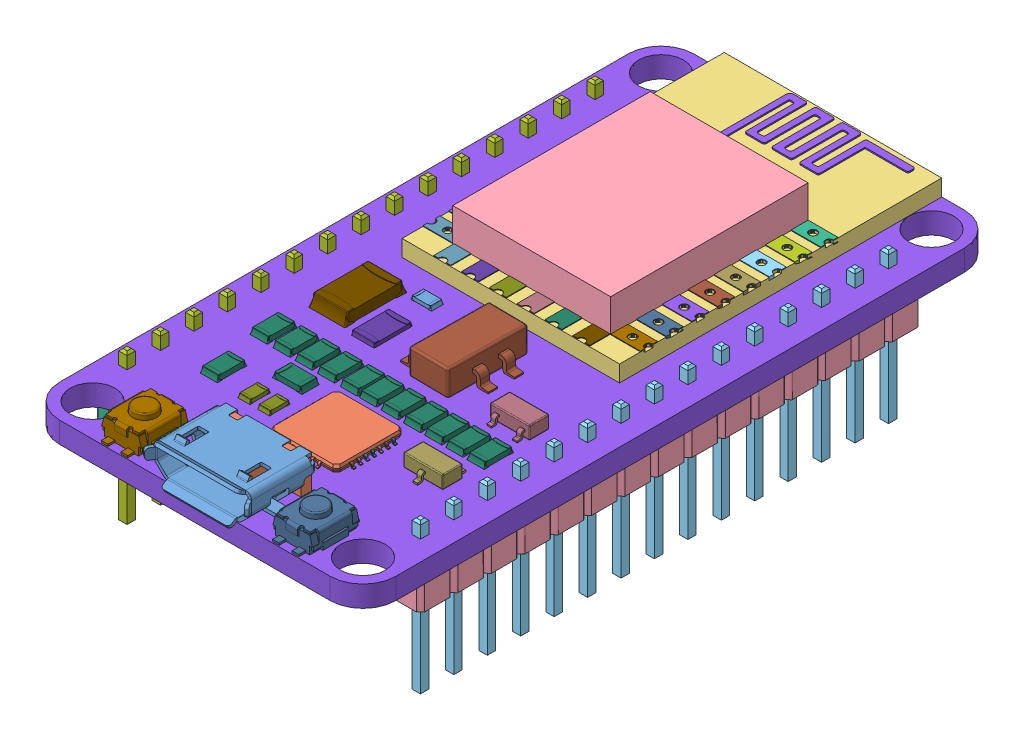
SolidWorks assembly Nodemcu, configuration Default. Lengths in mm.
Overall size (25.55 14.09 48.82).
166 component instances, 58 part files, 0 mates.
Components (placement in the parent):
- ESP8266 v7.stp-1: ESP8266 v7.stp [Default] at origin size (25.55 14.09 48.82)
  - micro usb v1.stp-1: micro usb v1.stp [Default] at (12.6689 12.0548 1.95) x (0 -1 0) z (-1 0 0) size (3.25 6.18 8)
    - micro usb shell.stp-1: micro usb shell.stp [Default] at (10.11 -1.95 -0.7124) x (0 0 -1) z (0 1 0) size (8 2.95 5.63)
    - micro usb internal.stp-1: micro usb internal.stp [Default] at (10.36 -1.95 -0.7124) x (0 0 -1) z (0 1 0) size (6.9 2.9 4)
    - micro usb contact.stp-1: micro usb contact.stp [Default] at (10.36 -2.05 -2.0124) x (0 0 -1) z (0 1 0) size (0.2 1.3 4.65)
    - micro usb contact.stp-2: micro usb contact.stp [Default] at (10.36 -2.05 -1.3624) x (0 0 -1) z (0 1 0) size (0.2 1.3 4.65)
    - micro usb contact.stp-3: micro usb contact.stp [Default] at (10.36 -2.05 -0.7124) x (0 0 -1) z (0 1 0) size (0.2 1.3 4.65)
    - micro usb contact.stp-4: micro usb contact.stp [Default] at (10.36 -2.05 -0.0624) x (0 0 -1) z (0 1 0) size (0.2 1.3 4.65)
    - micro usb contact.stp-5: micro usb contact.stp [Default] at (10.36 -2.05 0.5876) x (0 0 -1) z (0 1 0) size (0.2 1.3 4.65)
  - Placa Base.stp-1: Placa Base.stp [Default] at origin size (25.55 11.43 48.19)
    - Pin Header 1x15 TH Pitch 2.54mm v3 v1.stp-1: Pin Header 1x15 TH Pitch 2.54mm v3 v1.stp [Default] at (24.996 0.1484 -10.5049) x (0 0 -1) z (0 1 0) size (38.1 2.54 11.43)
      - asm_pin.stp-1: asm_pin.stp [Default] at (-4.318 1.27 0.0014) x (1 0 0) z (0 0 -1) size (2.54 2.54 11.43)
        - spacer.stp-1: spacer.stp [Default] at origin size (2.54 2.54 2.54)
        - pin.stp-1: pin.stp [Default] at origin size (0.64 0.64 11.43)
      - asm_pin_1.stp-1: asm_pin_1.stp [Default] at (-1.778 1.27 0.0014) x (1 0 0) z (0 0 -1) size (2.54 2.54 11.43)
        - spacer.stp-1: spacer.stp [Default] at origin size (2.54 2.54 2.54)
        - pin.stp-1: pin.stp [Default] at origin size (0.64 0.64 11.43)
      - asm_pin_2.stp-1: asm_pin_2.stp [Default] at (0.762 1.27 0.0014) x (1 0 0) z (0 0 -1) size (2.54 2.54 11.43)
        - spacer.stp-1: spacer.stp [Default] at origin size (2.54 2.54 2.54)
        - pin.stp-1: pin.stp [Default] at origin size (0.64 0.64 11.43)
      - asm_pin_3.stp-1: asm_pin_3.stp [Default] at (3.302 1.27 0.0014) x (1 0 0) z (0 0 -1) size (2.54 2.54 11.43)
        - spacer.stp-1: spacer.stp [Default] at origin size (2.54 2.54 2.54)
        - pin.stp-1: pin.stp [Default] at origin size (0.64 0.64 11.43)
      - asm_pin_4.stp-1: asm_pin_4.stp [Default] at (5.842 1.27 0.0014) x (1 0 0) z (0 0 -1) size (2.54 2.54 11.43)
        - spacer.stp-1: spacer.stp [Default] at origin size (2.54 2.54 2.54)
        - pin.stp-1: pin.stp [Default] at origin size (0.64 0.64 11.43)
      - asm_pin_5.stp-1: asm_pin_5.stp [Default] at (8.382 1.27 0.0014) x (1 0 0) z (0 0 -1) size (2.54 2.54 11.43)
        - spacer.stp-1: spacer.stp [Default] at origin size (2.54 2.54 2.54)
        - pin.stp-1: pin.stp [Default] at origin size (0.64 0.64 11.43)
      - asm_pin_6.stp-1: asm_pin_6.stp [Default] at (10.922 1.27 0.0014) x (1 0 0) z (0 0 -1) size (2.54 2.54 11.43)
        - spacer.stp-1: spacer.stp [Default] at origin size (2.54 2.54 2.54)
        - pin.stp-1: pin.stp [Default] at origin size (0.64 0.64 11.43)
      - asm_pin_7.stp-1: asm_pin_7.stp [Default] at (13.462 1.27 0.0014) x (1 0 0) z (0 0 -1) size (2.54 2.54 11.43)
        - spacer.stp-1: spacer.stp [Default] at origin size (2.54 2.54 2.54)
        - pin.stp-1: pin.stp [Default] at origin size (0.64 0.64 11.43)
      - asm_pin_8.stp-1: asm_pin_8.stp [Default] at (16.002 1.27 0.0014) x (1 0 0) z (0 0 -1) size (2.54 2.54 11.43)
        - spacer.stp-1: spacer.stp [Default] at origin size (2.54 2.54 2.54)
        - pin.stp-1: pin.stp [Default] at origin size (0.64 0.64 11.43)
      - asm_pin_9.stp-1: asm_pin_9.stp [Default] at (18.542 1.27 0.0014) x (1 0 0) z (0 0 -1) size (2.54 2.54 11.43)
        - spacer.stp-1: spacer.stp [Default] at origin size (2.54 2.54 2.54)
        - pin.stp-1: pin.stp [Default] at origin size (0.64 0.64 11.43)
      - asm_pin_10.stp-1: asm_pin_10.stp [Default] at (21.082 1.27 0.0014) x (1 0 0) z (0 0 -1) size (2.54 2.54 11.43)
        - spacer.stp-1: spacer.stp [Default] at origin size (2.54 2.54 2.54)
        - pin.stp-1: pin.stp [Default] at origin size (0.64 0.64 11.43)
      - asm_pin_11.stp-1: asm_pin_11.stp [Default] at (23.622 1.27 0.0014) x (1 0 0) z (0 0 -1) size (2.54 2.54 11.43)
        - spacer.stp-1: spacer.stp [Default] at origin size (2.54 2.54 2.54)
        - pin.stp-1: pin.stp [Default] at origin size (0.64 0.64 11.43)
      - asm_pin_12.stp-1: asm_pin_12.stp [Default] at (26.1619 1.27 0.0014) x (1 0 0) z (0 0 -1) size (2.54 2.54 11.43)
        - spacer.stp-1: spacer.stp [Default] at origin size (2.54 2.54 2.54)
        - pin.stp-1: pin.stp [Default] at origin size (0.64 0.64 11.43)
      - asm_pin_13.stp-1: asm_pin_13.stp [Default] at (28.702 1.27 0.0014) x (1 0 0) z (0 0 -1) size (2.54 2.54 11.43)
        - spacer.stp-1: spacer.stp [Default] at origin size (2.54 2.54 2.54)
        - pin.stp-1: pin.stp [Default] at origin size (0.64 0.64 11.43)
      - asm_pin_14.stp-1: asm_pin_14.stp [Default] at (31.242 1.27 0.0014) x (1 0 0) z (0 0 -1) size (2.54 2.54 11.43)
        - spacer.stp-1: spacer.stp [Default] at origin size (2.54 2.54 2.54)
        - pin.stp-1: pin.stp [Default] at origin size (0.64 0.64 11.43)
    - Pin Header 1x15 TH Pitch 2.54mm v3 v1 (1) (1).stp-1: Pin Header 1x15 TH Pitch 2.54mm v3 v1 (1) (1).stp [Default] at (2.7074 0.1484 -10.5049) x (0 0 -1) z (0 1 0) size (38.1 2.54 11.43)
      - asm_pin (1) (1).stp-1: asm_pin (1) (1).stp [Default] at (-4.318 1.27 0.0014) x (1 0 0) z (0 0 -1) size (2.54 2.54 11.43)
        - spacer (1) (1).stp-1: spacer (1) (1).stp [Default] at origin size (2.54 2.54 2.54)
        - pin (1) (1).stp-1: pin (1) (1).stp [Default] at origin size (0.64 0.64 11.43)
      - asm_pin (1) (1)_1.stp-1: asm_pin (1) (1)_1.stp [Default] at (-1.778 1.27 0.0014) x (1 0 0) z (0 0 -1) size (2.54 2.54 11.43)
        - spacer (1) (1).stp-1: spacer (1) (1).stp [Default] at origin size (2.54 2.54 2.54)
        - pin (1) (1).stp-1: pin (1) (1).stp [Default] at origin size (0.64 0.64 11.43)
      - asm_pin (1) (1)_2.stp-1: asm_pin (1) (1)_2.stp [Default] at (0.762 1.27 0.0014) x (1 0 0) z (0 0 -1) size (2.54 2.54 11.43)
        - spacer (1) (1).stp-1: spacer (1) (1).stp [Default] at origin size (2.54 2.54 2.54)
        - pin (1) (1).stp-1: pin (1) (1).stp [Default] at origin size (0.64 0.64 11.43)
      - asm_pin (1) (1)_3.stp-1: asm_pin (1) (1)_3.stp [Default] at (3.302 1.27 0.0014) x (1 0 0) z (0 0 -1) size (2.54 2.54 11.43)
        - spacer (1) (1).stp-1: spacer (1) (1).stp [Default] at origin size (2.54 2.54 2.54)
        - pin (1) (1).stp-1: pin (1) (1).stp [Default] at origin size (0.64 0.64 11.43)
      - asm_pin (1) (1)_4.stp-1: asm_pin (1) (1)_4.stp [Default] at (5.842 1.27 0.0014) x (1 0 0) z (0 0 -1) size (2.54 2.54 11.43)
        - spacer (1) (1).stp-1: spacer (1) (1).stp [Default] at origin size (2.54 2.54 2.54)
        - pin (1) (1).stp-1: pin (1) (1).stp [Default] at origin size (0.64 0.64 11.43)
      - asm_pin (1) (1)_5.stp-1: asm_pin (1) (1)_5.stp [Default] at (8.382 1.27 0.0014) x (1 0 0) z (0 0 -1) size (2.54 2.54 11.43)
        - spacer (1) (1).stp-1: spacer (1) (1).stp [Default] at origin size (2.54 2.54 2.54)
        - pin (1) (1).stp-1: pin (1) (1).stp [Default] at origin size (0.64 0.64 11.43)
      - asm_pin (1) (1)_6.stp-1: asm_pin (1) (1)_6.stp [Default] at (10.922 1.27 0.0014) x (1 0 0) z (0 0 -1) size (2.54 2.54 11.43)
        - spacer (1) (1).stp-1: spacer (1) (1).stp [Default] at origin size (2.54 2.54 2.54)
        - pin (1) (1).stp-1: pin (1) (1).stp [Default] at origin size (0.64 0.64 11.43)
      - asm_pin (1) (1)_7.stp-1: asm_pin (1) (1)_7.stp [Default] at (13.462 1.27 0.0014) x (1 0 0) z (0 0 -1) size (2.54 2.54 11.43)
        - spacer (1) (1).stp-1: spacer (1) (1).stp [Default] at origin size (2.54 2.54 2.54)
        - pin (1) (1).stp-1: pin (1) (1).stp [Default] at origin size (0.64 0.64 11.43)
      - asm_pin (1) (1)_8.stp-1: asm_pin (1) (1)_8.stp [Default] at (16.002 1.27 0.0014) x (1 0 0) z (0 0 -1) size (2.54 2.54 11.43)
        - spacer (1) (1).stp-1: spacer (1) (1).stp [Default] at origin size (2.54 2.54 2.54)
        - pin (1) (1).stp-1: pin (1) (1).stp [Default] at origin size (0.64 0.64 11.43)
      - asm_pin (1) (1)_9.stp-1: asm_pin (1) (1)_9.stp [Default] at (18.542 1.27 0.0014) x (1 0 0) z (0 0 -1) size (2.54 2.54 11.43)
        - spacer (1) (1).stp-1: spacer (1) (1).stp [Default] at origin size (2.54 2.54 2.54)
        - pin (1) (1).stp-1: pin (1) (1).stp [Default] at origin size (0.64 0.64 11.43)
      - asm_pin (1) (1)_10.stp-1: asm_pin (1) (1)_10.stp [Default] at (21.082 1.27 0.0014) x (1 0 0) z (0 0 -1) size (2.54 2.54 11.43)
        - spacer (1) (1).stp-1: spacer (1) (1).stp [Default] at origin size (2.54 2.54 2.54)
        - pin (1) (1).stp-1: pin (1) (1).stp [Default] at origin size (0.64 0.64 11.43)
      - asm_pin (1) (1)_11.stp-1: asm_pin (1) (1)_11.stp [Default] at (23.622 1.27 0.0014) x (1 0 0) z (0 0 -1) size (2.54 2.54 11.43)
        - spacer (1) (1).stp-1: spacer (1) (1).stp [Default] at origin size (2.54 2.54 2.54)
        - pin (1) (1).stp-1: pin (1) (1).stp [Default] at origin size (0.64 0.64 11.43)
      - asm_pin (1) (1)_12.stp-1: asm_pin (1) (1)_12.stp [Default] at (26.1619 1.27 0.0014) x (1 0 0) z (0 0 -1) size (2.54 2.54 11.43)
        - spacer (1) (1).stp-1: spacer (1) (1).stp [Default] at origin size (2.54 2.54 2.54)
        - pin (1) (1).stp-1: pin (1) (1).stp [Default] at origin size (0.64 0.64 11.43)
      - asm_pin (1) (1)_13.stp-1: asm_pin (1) (1)_13.stp [Default] at (28.702 1.27 0.0014) x (1 0 0) z (0 0 -1) size (2.54 2.54 11.43)
        - spacer (1) (1).stp-1: spacer (1) (1).stp [Default] at origin size (2.54 2.54 2.54)
        - pin (1) (1).stp-1: pin (1) (1).stp [Default] at origin size (0.64 0.64 11.43)
      - asm_pin (1) (1)_14.stp-1: asm_pin (1) (1)_14.stp [Default] at (31.242 1.27 0.0014) x (1 0 0) z (0 0 -1) size (2.54 2.54 11.43)
        - spacer (1) (1).stp-1: spacer (1) (1).stp [Default] at origin size (2.54 2.54 2.54)
        - pin (1) (1).stp-1: pin (1) (1).stp [Default] at origin size (0.64 0.64 11.43)
    - Placa Base-0.stp-1: Placa Base-0.stp [Default] at origin size (25.55 1.6 48.19)
  - switch v1.stp-1: switch v1.stp [Default] at (-4.6798 0 12.1544) x (1 0 0) z (0 1 0) size (3 4.6 1.85)
  - switch v1 (1).stp-1: switch v1 (1).stp [Default] at (8.3273 0 12.1544) x (1 0 0) z (0 1 0) size (3 4.6 1.85)
  - TSOP-5 v4 v1.stp-1: TSOP-5 v4 v1.stp [Default] at (-0.2513 -0.1563 0.1159) x (-0.013485 0 0.999909) z (0 1 0) size (6 5.43 2.1)
  - TSOP-5 v4 v1 (1).stp-1: TSOP-5 v4 v1 (1).stp [Default] at (20.2211 1.5986 -10.6444) x (1 0 0) z (0 1 0) size (3 2.71 1.05)
  - TSOP-5 v4 v1 (1) (1).stp-1: TSOP-5 v4 v1 (1) (1).stp [Default] at (20.2211 1.5625 -17.2293) x (-1 0 0) z (0 1 0) size (3 2.71 1.05)
  - Component41.stp-1: Component41.stp [Default] at origin size (2.26 1.3 15)
  - R0805-NO v1.stp-1: R0805-NO v1.stp [Default] at (8.8909 1.5658 -11.5498) x (1 0 0) z (0 1 0) size (2.31 1.35 0.45)
  - R0805-NO v1.stp-2: R0805-NO v1.stp [Default] at (5.3832 1.5658 -9.5734) x (0 0 1) z (0 1 0) size (2.31 1.35 0.45)
  - R0805-NO v1.stp-3: R0805-NO v1.stp [Default] at (4.7384 1.5658 -14.0063) x (0 0 1) z (0 1 0) size (2.31 1.35 0.45)
  - R0805-NO v1.stp-4: R0805-NO v1.stp [Default] at (21.2208 1.5658 -14.0063) x (0 0 1) z (0 1 0) size (2.31 1.35 0.45)
  - R0805-NO v1.stp-5: R0805-NO v1.stp [Default] at (19.6088 1.5658 -14.0063) x (0 0 1) z (0 1 0) size (2.31 1.35 0.45)
  - R0805-NO v1.stp-6: R0805-NO v1.stp [Default] at (17.9968 1.5658 -14.0063) x (0 0 1) z (0 1 0) size (2.31 1.35 0.45)
  - R0805-NO v1.stp-7: R0805-NO v1.stp [Default] at (16.3849 1.5658 -14.0063) x (0 0 1) z (0 1 0) size (2.31 1.35 0.45)
  - R0805-NO v1.stp-8: R0805-NO v1.stp [Default] at (14.6923 1.5658 -14.0063) x (0 0 1) z (0 1 0) size (2.31 1.35 0.45)
  - R0805-NO v1.stp-9: R0805-NO v1.stp [Default] at (13.04 1.5658 -14.0063) x (0 0 1) z (0 1 0) size (2.31 1.35 0.45)
  - R0805-NO v1.stp-10: R0805-NO v1.stp [Default] at (11.5893 1.5658 -14.0063) x (0 0 1) z (0 1 0) size (2.31 1.35 0.45)
  - R0805-NO v1.stp-11: R0805-NO v1.stp [Default] at (9.8564 1.5658 -14.0063) x (0 0 1) z (0 1 0) size (2.31 1.35 0.45)
  - R0805-NO v1.stp-12: R0805-NO v1.stp [Default] at (8.1638 1.5658 -14.0063) x (0 0 1) z (0 1 0) size (2.31 1.35 0.45)
  - R0805-NO v1.stp-13: R0805-NO v1.stp [Default] at (6.4713 1.5658 -14.0063) x (0 0 1) z (0 1 0) size (2.31 1.35 0.45)
  - R0805-NO v1 (1).stp-1: R0805-NO v1 (1).stp [Default] at (8.4415 1.5658 -9.3168) x (0 0 1) z (0 1 0) size (1.62 0.95 0.32)
  - R0805-NO v1 (1).stp-2: R0805-NO v1 (1).stp [Default] at (9.9358 1.5658 -9.3168) x (0 0 1) z (0 1 0) size (1.62 0.95 0.32)
  - R0805-NO v1 (1) (1).stp-1: R0805-NO v1 (1) (1).stp [Default] at (8.597 1.5658 -17.758) x (0 0 1) z (0 1 0) size (3.23 1.9 0.64)
  - R0805-NO v1 (1) (2).stp-1: R0805-NO v1 (1) (2).stp [Default] at (4.6179 1.5658 -48.9696) x (0 0 1) z (0 1 0) size (4.84 2.84 0.96)
  - R0805-NO v1 (1) (3).stp-1: R0805-NO v1 (1) (3).stp [Default] at (8.3907 1.5658 -21.9299) x (1 0 0) z (0 1 0) size (1.62 0.95 0.32)
  - Cuerpo Microprocesador v1.stp-1: Cuerpo Microprocesador v1.stp [Default] at (13.4174 0.8784 -8.5282) size (5.17 0.51 5.78)
  - ESP8266 v7.stp-1: ESP8266 v7.stp [Default] at origin size (16.52 1.25 24.48)
  - ESP8266 v7-1.stp-1: ESP8266 v7-1.stp [Default] at origin size (12 3.75 15)
  - ESP8266 v7-2.stp-1: ESP8266 v7-2.stp [Default] at origin size (2.25 1.3 1.29)
  - ESP8266 v7-3.stp-1: ESP8266 v7-3.stp [Default] at origin size (2.25 1.3 1.29)
  - ESP8266 v7-4.stp-1: ESP8266 v7-4.stp [Default] at origin size (2.25 1.3 1.29)
  - ESP8266 v7-5.stp-1: ESP8266 v7-5.stp [Default] at origin size (2.25 1.3 1.29)
  - ESP8266 v7-6.stp-1: ESP8266 v7-6.stp [Default] at origin size (2.25 1.3 1.29)
  - ESP8266 v7-7.stp-1: ESP8266 v7-7.stp [Default] at origin size (2.25 1.3 1.29)
  - ESP8266 v7-8.stp-1: ESP8266 v7-8.stp [Default] at origin size (2.25 1.3 1.29)
  - ESP8266 v7-9.stp-1: ESP8266 v7-9.stp [Default] at origin size (2.25 1.3 1.29)
  - ESP8266 v7-10.stp-1: ESP8266 v7-10.stp [Default] at origin size (1.29 1.3 1.54)
  - ESP8266 v7-11.stp-1: ESP8266 v7-11.stp [Default] at origin size (1.29 1.3 1.54)
  - ESP8266 v7-12.stp-1: ESP8266 v7-12.stp [Default] at origin size (1.29 1.3 1.54)
  - ESP8266 v7-13.stp-1: ESP8266 v7-13.stp [Default] at origin size (1.29 1.3 1.54)
  - ESP8266 v7-14.stp-1: ESP8266 v7-14.stp [Default] at origin size (1.29 1.3 1.54)
  - ESP8266 v7-15.stp-1: ESP8266 v7-15.stp [Default] at origin size (1.29 1.3 1.54)
  - ESP8266 v7-16.stp-1: ESP8266 v7-16.stp [Default] at origin size (2.26 0.13 1.29)
  - ESP8266 v7-17.stp-1: ESP8266 v7-17.stp [Default] at origin size (2.26 0.13 1.29)
  - ESP8266 v7-18.stp-1: ESP8266 v7-18.stp [Default] at origin size (2.26 0.13 1.29)
  - ESP8266 v7-19.stp-1: ESP8266 v7-19.stp [Default] at origin size (2.26 0.13 1.29)
  - ESP8266 v7-20.stp-1: ESP8266 v7-20.stp [Default] at origin size (2.26 0.13 1.29)
  - ESP8266 v7-21.stp-1: ESP8266 v7-21.stp [Default] at origin size (2.26 0.13 1.29)
  - ESP8266 v7-22.stp-1: ESP8266 v7-22.stp [Default] at origin size (2.26 0.13 1.29)
  - ESP8266 v7-23.stp-1: ESP8266 v7-23.stp [Default] at origin size (9.75 0.1 6.42)
  - ESP8266 v7-24.stp-1: ESP8266 v7-24.stp [Default] at origin size (0.38 0.31 0.17)
  - ESP8266 v7-25.stp-1: ESP8266 v7-25.stp [Default] at origin size (0.38 0.31 0.17)
  - ESP8266 v7-26.stp-1: ESP8266 v7-26.stp [Default] at origin size (0.38 0.31 0.17)
  - ESP8266 v7-27.stp-1: ESP8266 v7-27.stp [Default] at origin size (0.38 0.31 0.17)
  - ESP8266 v7-28.stp-1: ESP8266 v7-28.stp [Default] at origin size (0.38 0.31 0.17)
  - ESP8266 v7-29.stp-1: ESP8266 v7-29.stp [Default] at origin size (0.38 0.31 0.18)
  - ESP8266 v7-30.stp-1: ESP8266 v7-30.stp [Default] at origin size (0.38 0.31 0.17)
  - ESP8266 v7-31.stp-1: ESP8266 v7-31.stp [Default] at origin size (0.38 0.31 0.17)
  - ESP8266 v7-32.stp-1: ESP8266 v7-32.stp [Default] at origin size (0.38 0.31 0.17)
  - ESP8266 v7-33.stp-1: ESP8266 v7-33.stp [Default] at origin size (0.38 0.31 0.17)
  - ESP8266 v7-34.stp-1: ESP8266 v7-34.stp [Default] at origin size (0.38 0.31 0.17)
  - ESP8266 v7-35.stp-1: ESP8266 v7-35.stp [Default] at origin size (0.38 0.31 0.17)
  - ESP8266 v7-36.stp-1: ESP8266 v7-36.stp [Default] at origin size (0.38 0.31 0.17)
  - ESP8266 v7-37.stp-1: ESP8266 v7-37.stp [Default] at origin size (0.38 0.31 0.18)
